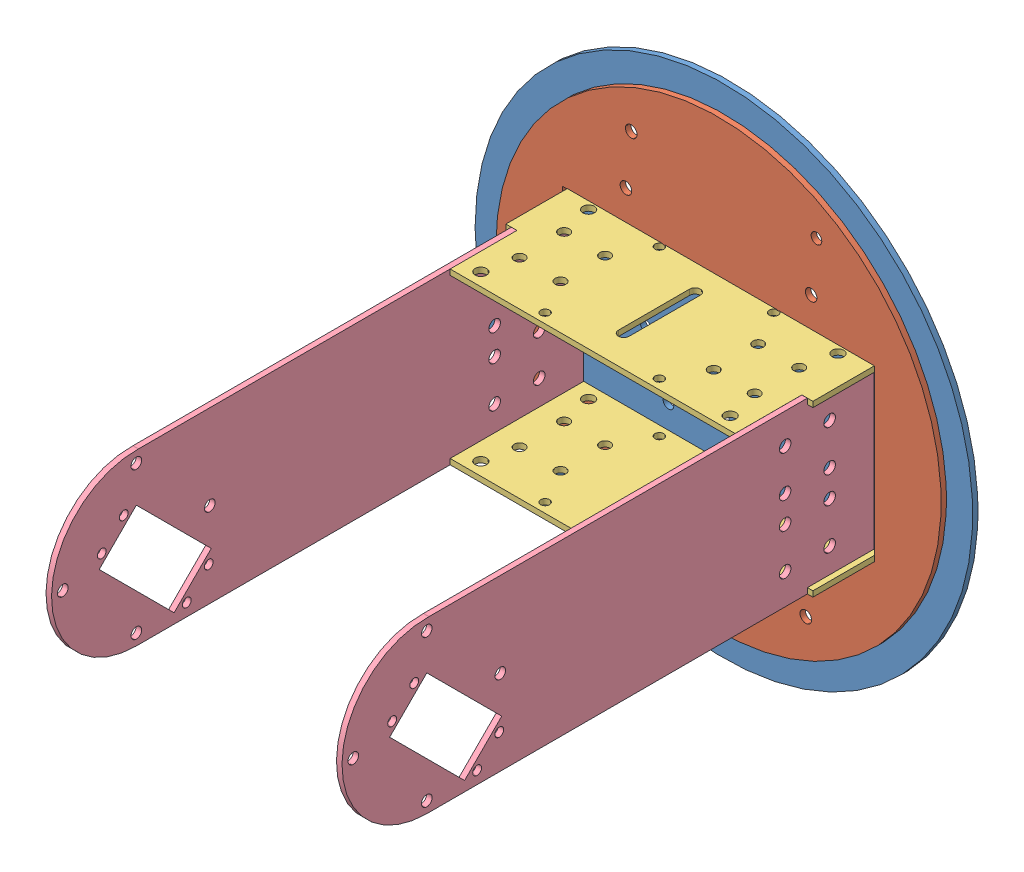
SolidWorks assembly BASE, configuration Default. Lengths in mm.
Overall size (279.4 279.4 301.82).
6 component instances, 4 part files, 13 mates.
Components (placement in the parent):
- base2-1: base2 [Default] at origin size (279.4 279.4 3)
- base1-2: base1 [Default] at (0 0 3) size (250 250 3)
- base3-1: base3 [Default] at (1.3 -44.4 40.5) x (1 0 0) z (0 -1 0) size (172.4 75 3.1)
- base4-1: base4 [Default] at (81.3 0.125 254.1969) x (0 0 -1) z (1 0 0) size (298.82 95.25 3.1)
- base3-3: base3 [Default] at (1.3 47.75 40.5) x (1 0 0) z (0 -1 0) size (172.4 75 3.1)
- base4-3: base4 [Default] at (-81.8 0.14 254.1969) x (0 0 -1) z (1 0 0) size (298.82 95.25 3.1)
Mates (geometry in assembly coordinates):
- Concentric1: concentric aligned: circle of base2-1; circle of base1-2
- Concentric2: concentric aligned: circle of base2-1; circle of base1-2
- Coincident1: coincident aligned: plane of base2-1 through (0 0 3) normal (0 0 1); circle of base1-2
- Coincident2: coincident aligned: line of base1-2 through (-87.5 -47.5 3) axis (1 0 0); line of base3-1 through (-84.9 -47.5 3) axis (1 0 0)
- Coincident3: coincident anti-aligned: plane of base1-2 through (-87.5 -47.5 6) normal (0 1 0); plane of base3-1 through (1.3 -47.5 40.5) normal (0 -1 0)
- Coincident4: coincident: line of base1-2 through (87.5 -47.5 6) axis (0 1 0); plane of base3-1 through (87.5 -44.4 40.5) normal (1 0 0)
- Coincident7: coincident: plane of base2-1 through (0 0 3) normal (0 0 1); line of base4-1 through (84.4 -44.4 3) axis (0 1 0)
- Coincident8: coincident anti-aligned: line of base3-1 through (81.3 -47.5 40.5) axis (0 0 1); line of base4-1 through (81.3 -47.5 254.1969) axis (0 0 -1)
- Parallel1: parallel aligned: line of base1-2 through (87.5 -47.5 6) axis (0 1 0); line of base4-1 through (84.4 -44.4 3) axis (0 1 0)
- Coincident10: coincident anti-aligned: plane of base2-1 through (0 0 3) normal (0 0 1); plane of base3-3 through (-78.7 44.65 3) normal (0 0 -1)
- Coincident11: coincident aligned: line of base4-1 through (81.3 44.65 3) axis (0 0 1); line of base3-3 through (81.3 44.65 40.5) axis (0 0 1)
- Coincident13: coincident: line of base3-3 through (-78.7 47.75 40.5) axis (-1 0 0); line of base4-3 through (-81.8 47.75 40.5) axis (1 0 0)
- Coincident14: coincident anti-aligned: line of base3-3 through (-78.7 47.75 78) axis (0 0 -1); line of base4-3 through (-78.7 47.75 40.5) axis (0 0 1)
